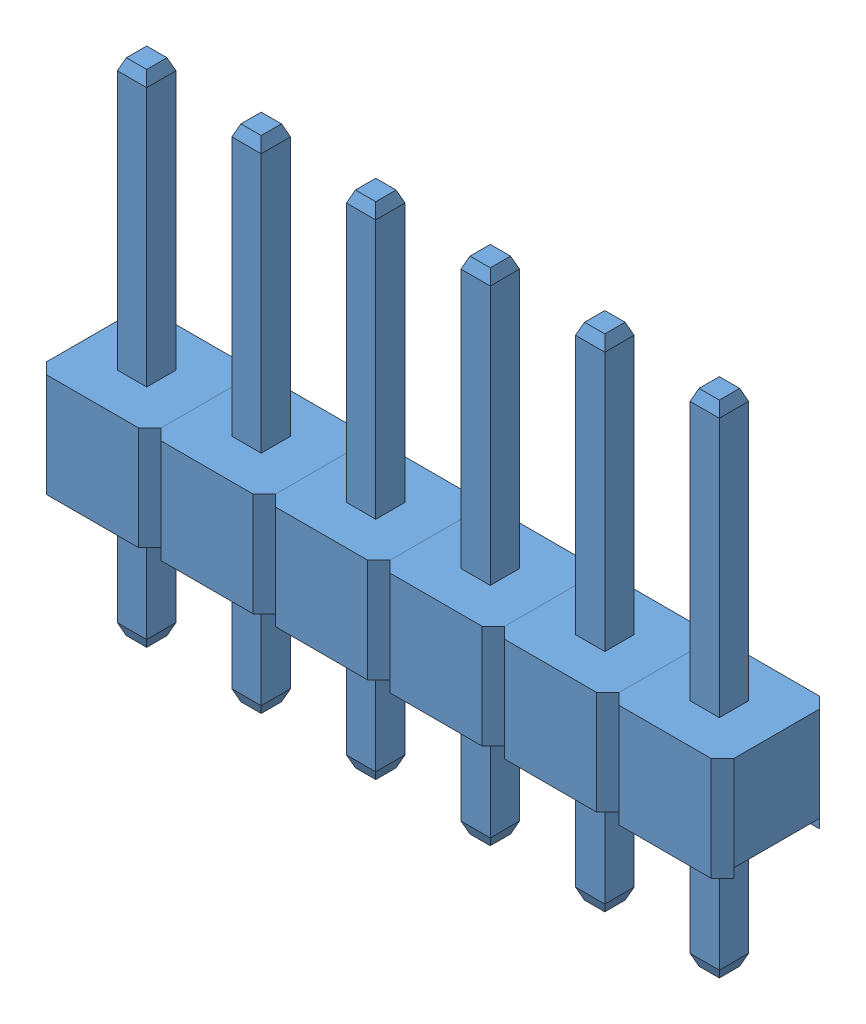
SolidWorks assembly 6x_Male_Pin_2.54_mm.STEP, configuration Default. Lengths in mm.
Overall size (15.24 11.1 2.4).
6 component instances, 1 part files, 0 mates.
Components (placement in the parent):
- 1_Male_Pin_2.54_mm.STEP-1: 1_Male_Pin_2.54_mm.STEP [Default] at (3.8763 2.2562 11.0637) size (2.54 11.1 2.4)
- 1_Male_Pin_2.54_mm.STEP-2: 1_Male_Pin_2.54_mm.STEP [Default] at (1.3363 2.2562 11.0637) size (2.54 11.1 2.4)
- 1_Male_Pin_2.54_mm.STEP-3: 1_Male_Pin_2.54_mm.STEP [Default] at (-1.2037 2.2562 11.0637) size (2.54 11.1 2.4)
- 1_Male_Pin_2.54_mm.STEP-4: 1_Male_Pin_2.54_mm.STEP [Default] at (-3.7437 2.2562 11.0637) size (2.54 11.1 2.4)
- 1_Male_Pin_2.54_mm.STEP-5: 1_Male_Pin_2.54_mm.STEP [Default] at (-6.2837 2.2562 11.0637) size (2.54 11.1 2.4)
- 1_Male_Pin_2.54_mm.STEP-6: 1_Male_Pin_2.54_mm.STEP [Default] at (-8.8237 2.2562 11.0637) size (2.54 11.1 2.4)
